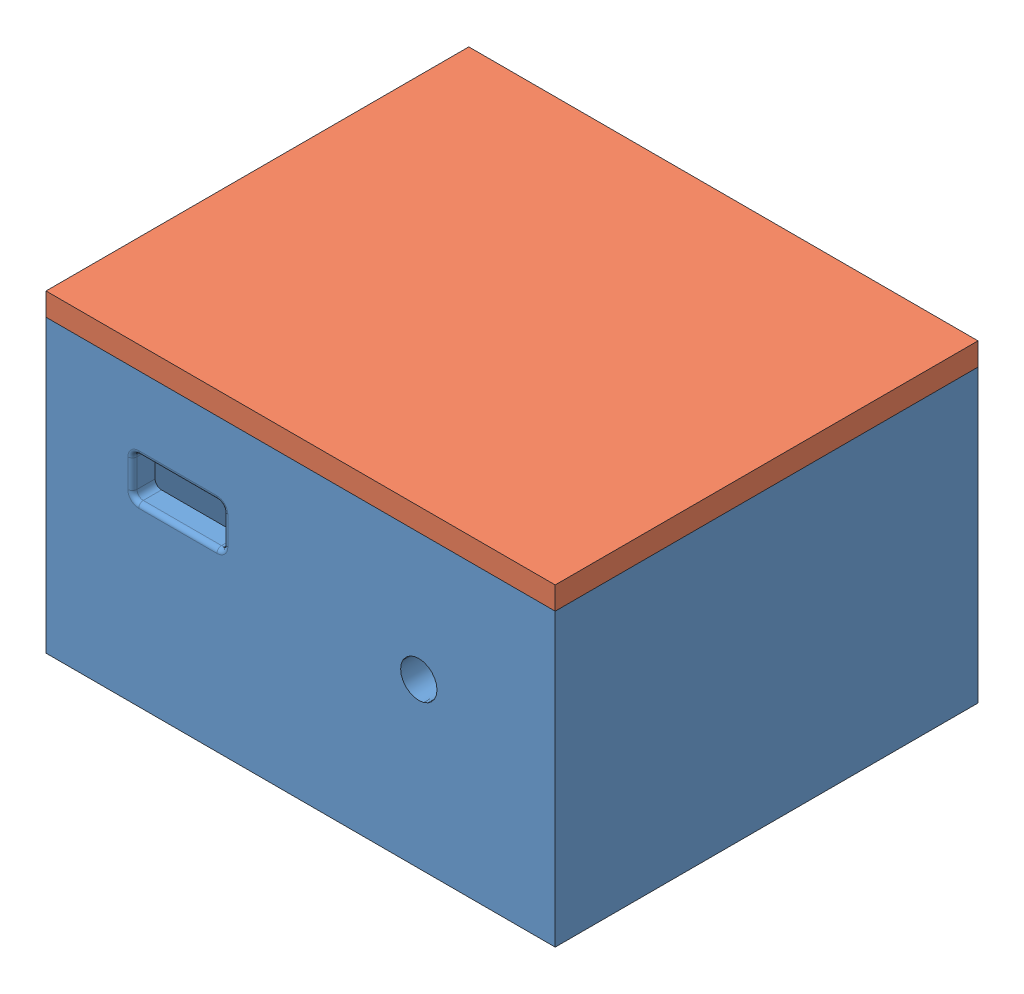
SolidWorks assembly Assem1, configuration Default. Lengths in mm.
Overall size (56 34.5 46.5).
2 component instances, 2 part files, 3 mates.
Components (placement in the parent):
- caja-1: caja [Default] at (9.8917 -26.9737 2.2356) size (56 32 46.5)
- tapa-1: tapa [Default] at (9.8917 5.0263 2.2356) size (56 5 46.5)
Mates (geometry in assembly coordinates):
- Coincident1: coincident: plane of assembly; plane of assembly; plane of caja-1 through (37.8917 5.0263 2.2356) normal (1 0 0); plane of tapa-1 through (37.8917 7.5263 -21.0144) normal (1 0 0)
- Coincident2: coincident: plane of assembly; plane of assembly; plane of caja-1 through (9.8917 5.0263 25.4856) normal (0 0 1); plane of tapa-1 through (-18.1083 7.5263 25.4856) normal (0 0 1)
- Coincident3: coincident: plane of assembly; plane of assembly; plane of caja-1 through (9.8917 5.0263 2.2356) normal (0 1 0); plane of tapa-1 through (9.8917 5.0263 2.2356) normal (0 -1 0)
